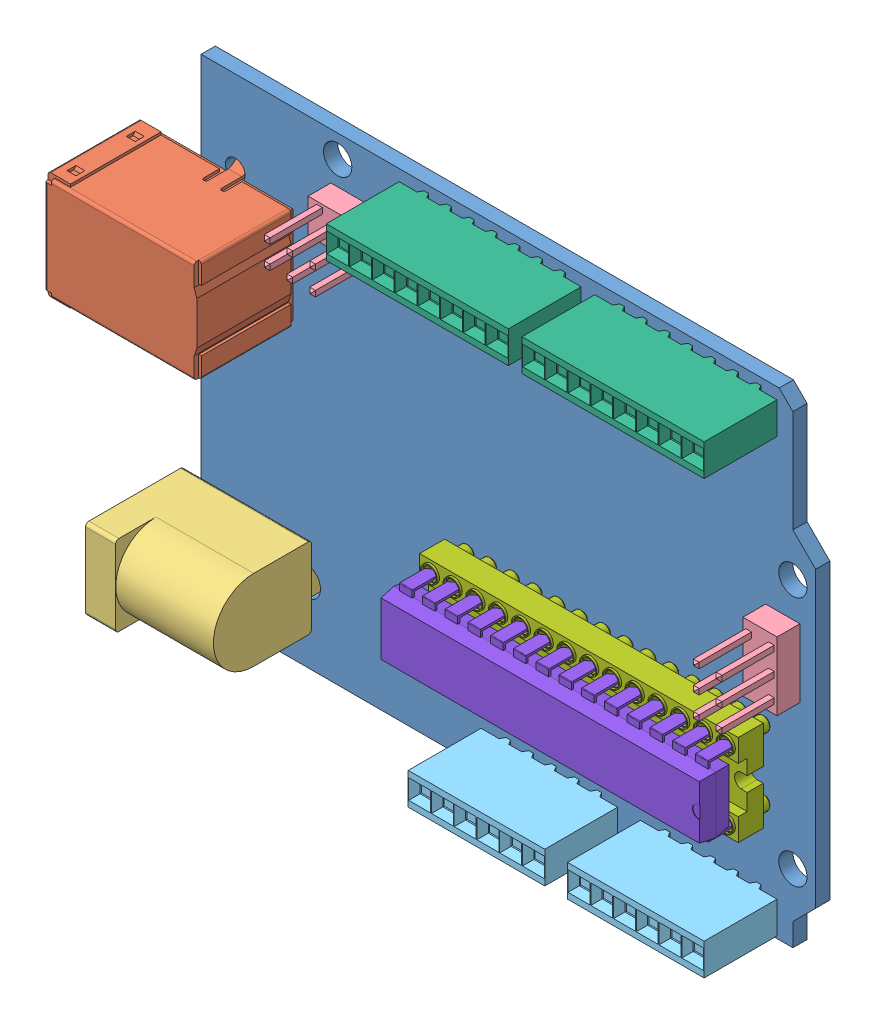
SolidWorks assembly uno-assy, configuration Default. Lengths in mm.
Overall size (75.05 53.34 15.91).
11 component instances, 8 part files, 29 mates.
Components (placement in the parent):
- uno-pcb-1: uno-pcb [Default] at origin size (68.58 53.34 1.59)
- SW3dPS-67068-0000-molex-1: SW3dPS-67068-0000-molex [Default] at (-40.7599 11.4299 0) x (0 -1 0) z (-1 0 0) size (14.9 15.43 17)
- RAPC732-1: RAPC732 [Default] at (-21.9709 -14.1224 0) x (0 -1 0) z (-1 0 0) size (9.47 14.4 14.25)
- 3x2-100-1: 3x2-100 [Default] at (-18.5421 20.828 0) size (7.62 3.81 11.94)
- 3x2-100-2: 3x2-100 [Default] at (29.3502 -1.32 0) x (0 1 0) z (0 0 1) size (7.62 3.81 11.94)
- C-0534237-04-3-1: C-0534237-04-3 [Default] at (22.8599 -24.13 8.636) x (-1 0 0) z (0 0 1) size (15.24 3.56 11.56)
- C-0534237-06-3-1: C-0534237-06-3 [Default] at (20.3199 24.13 8.636) x (-1 0 0) z (0 0 1) size (20.32 3.56 11.56)
- C-0534237-04-3-2: C-0534237-04-3 [Default] at (5.0799 -24.13 8.636) x (-1 0 0) z (0 0 1) size (15.24 3.56 11.56)
- C-0534237-06-3-2: C-0534237-06-3 [Default] at (-1.5241 24.13 8.636) x (-1 0 0) z (0 0 1) size (20.32 3.56 11.56)
- 28pdipskt-1: 28pdipskt [Default] at (24.7649 -10.287 1.4) x (0 -1 0) z (0 0 1) size (10.16 35.56 7.62)
- User Library-28 pin dip-1: User Library-28 pin dip [Default] at (6.9849 -10.287 6.873) x (0 1 0) z (1 0 0) size (7.87 6.22 35.94)
Mates (geometry in assembly coordinates):
- Coincident1: coincident aligned: axis of uno-pcb-1 through (-27.7699 12.6799 -1.5875) axis (0 0 1); axis of SW3dPS-67068-0000-molex-1 through (-27.7699 12.6799 -2.8) axis (0 0 1)
- Coincident2: coincident anti-aligned: plane of uno-pcb-1 through (-34.2899 26.67 0) normal (0 0 1); plane of SW3dPS-67068-0000-molex-1 through (-23.7599 17.4299 0) normal (0 0 -1)
- Parallel1: parallel aligned: plane of uno-pcb-1 through (-34.2899 -26.67 -1.5875) normal (-1 0 0); plane of SW3dPS-67068-0000-molex-1 through (-40.7599 17.4299 11) normal (-1 0 0)
- Concentric1: concentric aligned: circle of uno-pcb-1; circle of RAPC732-1
- Parallel2: parallel aligned: plane of uno-pcb-1 through (-34.2899 -26.67 -1.5875) normal (-1 0 0); plane of RAPC732-1 through (-36.2203 -14.5034 10.5918) normal (-1 0 0)
- Coincident5: coincident anti-aligned: plane of uno-pcb-1 through (-34.2899 26.67 0) normal (0 0 1); plane of RAPC732-1 through (-36.2203 -14.5034 0) normal (0 0 -1)
- Coincident6: coincident aligned: axis of uno-pcb-1 through (-18.5421 18.288 -1.5875) axis (0 0 1); axis of 3x2-100-1 through (-18.5421 18.288 -3.302) axis (0 0 1)
- Coincident7: coincident anti-aligned: plane of uno-pcb-1 through (-34.2899 26.67 0) normal (0 0 1); plane of 3x2-100-1 through (-18.5421 20.828 0) normal (0 0 -1)
- Coincident8: coincident aligned: axis of uno-pcb-1 through (31.8902 -1.32 -1.5875) axis (0 0 1); axis of 3x2-100-2 through (31.8902 -1.32 -3.302) axis (0 0 1)
- Coincident9: coincident anti-aligned: plane of uno-pcb-1 through (-34.2899 26.67 0) normal (0 0 1); plane of 3x2-100-2 through (29.3502 -1.32 0) normal (0 0 -1)
- Parallel3: parallel anti-aligned: plane of uno-pcb-1 through (34.2899 -21.59 -1.5875) normal (1 0 0); plane of 3x2-100-2 through (28.7152 -2.59 2.54) normal (-1 0 0)
- Parallel4: parallel aligned: plane of uno-pcb-1 through (-34.2899 26.67 -1.5875) normal (0 1 0); plane of 3x2-100-1 through (-19.8121 21.463 2.54) normal (0 1 0)
- Coincident12: coincident anti-aligned: axis of uno-pcb-1 through (29.2099 -24.13 -1.5875) axis (0 0 1); axis of C-0534237-04-3-1 through (29.2099 -24.13 -0.846) axis (0 0 -1)
- Parallel5: parallel aligned: plane of uno-pcb-1 through (-34.2899 -26.67 -1.5875) normal (0 -1 0); plane of C-0534237-04-3-1 through (30.4799 -25.908 8.636) normal (0 -1 0)
- Coincident15: coincident anti-aligned: axis of uno-pcb-1 through (11.4299 -24.13 -1.5875) axis (0 0 1); axis of C-0534237-04-3-2 through (11.4299 -24.13 -0.846) axis (0 0 -1)
- Coincident16: coincident anti-aligned: plane of uno-pcb-1 through (-34.2899 26.67 0) normal (0 0 1); plane of C-0534237-04-3-2 through (10.4139 -25.908 0) normal (0 0 -1)
- Coincident17: coincident anti-aligned: plane of uno-pcb-1 through (-34.2899 26.67 0) normal (0 0 1); plane of C-0534237-04-3-1 through (28.1939 -25.908 0) normal (0 0 -1)
- Coincident18: coincident anti-aligned: axis of uno-pcb-1 through (29.2099 24.13 -1.5875) axis (0 0 1); axis of C-0534237-06-3-1 through (29.2099 24.13 -1.201) axis (0 0 -1)
- Coincident19: coincident anti-aligned: plane of uno-pcb-1 through (-34.2899 26.67 0) normal (0 0 1); plane of C-0534237-06-3-1 through (28.1939 25.908 0) normal (0 0 -1)
- Parallel6: parallel aligned: plane of uno-pcb-1 through (-34.2899 26.67 -1.5875) normal (0 1 0); plane of C-0534237-06-3-1 through (10.1599 25.908 8.636) normal (0 1 0)
- Coincident21: coincident anti-aligned: axis of uno-pcb-1 through (7.3659 24.13 -1.5875) axis (0 0 1); axis of C-0534237-06-3-2 through (7.3659 24.13 -1.201) axis (0 0 -1)
- Coincident22: coincident anti-aligned: plane of uno-pcb-1 through (-34.2899 26.67 0) normal (0 0 1); plane of C-0534237-06-3-2 through (6.3499 25.908 0) normal (0 0 -1)
- Parallel7: parallel aligned: plane of uno-pcb-1 through (-34.2899 26.67 -1.5875) normal (0 1 0); plane of C-0534237-06-3-2 through (-11.6841 25.908 8.636) normal (0 1 0)
- Coincident25: coincident aligned: axis of uno-pcb-1 through (28.5749 -6.477 -1.5875) axis (0 0 1); axis of 28pdipskt-1 through (28.5749 -6.477 -3.18) axis (0 0 1)
- Parallel8: parallel aligned: plane of uno-pcb-1 through (-34.2899 -26.67 -1.5875) normal (0 -1 0); plane of 28pdipskt-1 through (-5.7151 -15.367 4.19) normal (0 -1 0)
- Coincident27: coincident anti-aligned: plane of uno-pcb-1 through (-34.2899 26.67 0) normal (0 0 1); plane of 28pdipskt-1 through (28.5749 -14.097 0) normal (0 0 -1)
- Coincident28: coincident aligned: axis of 28pdipskt-1 through (28.5749 -6.477 4.19) axis (0 0 -1); axis of User Library-28 pin dip-1 through (28.5749 -6.477 2.508) axis (0 0 -1)
- Parallel9: parallel aligned: line of uno-pcb-1 through (-34.2899 -26.67 0) axis (1 0 0); line of User Library-28 pin dip-1 through (-5.7028 -13.2593 8.524) axis (1 0 0)
- Distance1: distance = 2.032 mm anti-aligned: plane of 28pdipskt-1 through (-5.7151 -7.707 3.19) normal (0 0 1); plane of User Library-28 pin dip-1 through (19.8754 -13.462 5.222) normal (0 0 -1)
